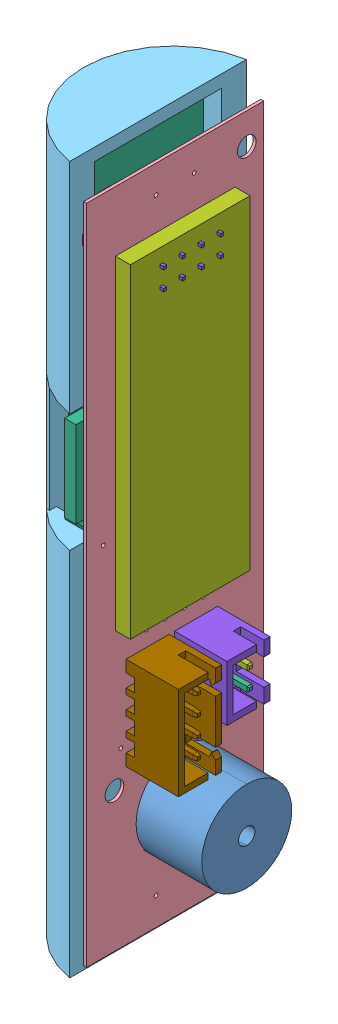
SolidWorks assembly electronics module, configuration Default. Lengths in mm.
Overall size (21.83 94.3 23.62).
277 component instances, 45 part files, 19 mates.
Components (placement in the parent):
- PCB-1: PCB [Default] at (20.7064 167.5504 -10.283) x (0 -1 0) z (-1 0 0) size (88.26 23.62 14)
  - R05-1: R05 [Default] at origin size (0.95 1.7 0.6)
    - 959206216-1: 959206216 [Default] at (123.9521 73.9609 0) size (0.95 0.27 0.6)
      - Extruded-1: Extruded [Default] at origin size (0.95 0.27 0.6)
    - 959206352-1: 959206352 [Default] at (123.9521 74.6759 0) size (0.95 1.16 0.6)
      - Extruded-1-1: Extruded-1 [Default] at origin size (0.95 1.16 0.6)
    - 959206216-2: 959206216 [Default] at (123.9521 75.3909 0) size (0.95 0.27 0.6)
      - Extruded-1: Extruded [Default] at origin size (0.95 0.27 0.6)
  - R04-1: R04 [Default] at origin size (0.95 1.7 0.6)
    - 959206216-1: 959206216 [Default] at (141.478 81.581 0) size (0.95 0.27 0.6)
      - Extruded-1: Extruded [Default] at origin size (0.95 0.27 0.6)
    - 959206352-1: 959206352 [Default] at (141.478 82.296 0) size (0.95 1.16 0.6)
      - Extruded-1-1: Extruded-1 [Default] at origin size (0.95 1.16 0.6)
    - 959206216-2: 959206216 [Default] at (141.478 83.011 0) size (0.95 0.27 0.6)
      - Extruded-1: Extruded [Default] at origin size (0.95 0.27 0.6)
  - R03-1: R03 [Default] at origin size (3.35 1.75 0.75)
    - 959206760-1: 959206760 [Default] at (147.8506 77.6516 0) size (0.49 1.75 0.75)
      - Extruded-2-1: Extruded-2 [Default] at origin size (0.49 1.75 0.75)
    - 959206896-1: 959206896 [Default] at (149.2781 77.6516 0) size (2.36 1.75 0.75)
      - Extruded-3-1: Extruded-3 [Default] at origin size (2.36 1.75 0.75)
    - 959206760-2: 959206760 [Default] at (150.7056 77.6516 0) size (0.49 1.75 0.75)
      - Extruded-2-1: Extruded-2 [Default] at origin size (0.49 1.75 0.75)
  - R02-1: R02 [Default] at origin size (1.75 3.35 0.75)
    - 959207032-1: 959207032 [Default] at (128.1431 81.3844 0) size (1.75 0.49 0.75)
      - Extruded-4-1: Extruded-4 [Default] at origin size (1.75 0.49 0.75)
    - 959207168-1: 959207168 [Default] at (128.1431 79.9569 0) size (1.75 2.36 0.75)
      - Extruded-5-1: Extruded-5 [Default] at origin size (1.75 2.36 0.75)
    - 959207032-2: 959207032 [Default] at (128.1431 78.5294 0) size (1.75 0.49 0.75)
      - Extruded-4-1: Extruded-4 [Default] at origin size (1.75 0.49 0.75)
  - R01-1: R01 [Default] at origin size (3.35 1.75 0.75)
    - 959206760-1: 959206760 [Default] at (117.3285 91.9479 0) size (0.49 1.75 0.75)
      - Extruded-2-1: Extruded-2 [Default] at origin size (0.49 1.75 0.75)
    - 959206896-1: 959206896 [Default] at (115.901 91.9479 0) size (2.36 1.75 0.75)
      - Extruded-3-1: Extruded-3 [Default] at origin size (2.36 1.75 0.75)
    - 959206760-2: 959206760 [Default] at (114.4735 91.9479 0) size (0.49 1.75 0.75)
      - Extruded-2-1: Extruded-2 [Default] at origin size (0.49 1.75 0.75)
  - U3-1: U3 [Default] at origin size (43.25 15.95 5.5)
    - 959206080-1: 959206080 [Default] at (102.177 84.441 -2.3912) size (43.25 15.95 2)
      - Extruded-6-1: Extruded-6 [Default] at origin size (43.25 15.95 2)
    - 959205944-1: 959205944 [Default] at (85.217 88.291 -2.8912) size (0.4 0.4 5.5)
      - Extruded-7-1: Extruded-7 [Default] at origin size (0.4 0.4 5.5)
    - 959205944-2: 959205944 [Default] at (85.217 85.751 -2.8912) size (0.4 0.4 5.5)
      - Extruded-7-1: Extruded-7 [Default] at origin size (0.4 0.4 5.5)
    - 959205944-3: 959205944 [Default] at (82.677 88.291 -2.8912) size (0.4 0.4 5.5)
      - Extruded-7-1: Extruded-7 [Default] at origin size (0.4 0.4 5.5)
    - 959205944-4: 959205944 [Default] at (82.677 85.751 -2.8912) size (0.4 0.4 5.5)
      - Extruded-7-1: Extruded-7 [Default] at origin size (0.4 0.4 5.5)
    - 959205944-5: 959205944 [Default] at (85.217 83.211 -2.8912) size (0.4 0.4 5.5)
      - Extruded-7-1: Extruded-7 [Default] at origin size (0.4 0.4 5.5)
    - 959205944-6: 959205944 [Default] at (85.217 80.671 -2.8912) size (0.4 0.4 5.5)
      - Extruded-7-1: Extruded-7 [Default] at origin size (0.4 0.4 5.5)
    - 959205944-7: 959205944 [Default] at (82.677 83.211 -2.8912) size (0.4 0.4 5.5)
      - Extruded-7-1: Extruded-7 [Default] at origin size (0.4 0.4 5.5)
    - 959205944-8: 959205944 [Default] at (82.677 80.671 -2.8912) size (0.4 0.4 5.5)
      - Extruded-7-1: Extruded-7 [Default] at origin size (0.4 0.4 5.5)
  - R11-1: R11 [Default] at origin size (1.35 2.2 0.7)
    - 959207304-1: 959207304 [Default] at (133.9849 94.0691 0) size (1.35 0.42 0.7)
      - Extruded-8-1: Extruded-8 [Default] at origin size (1.35 0.42 0.7)
    - 959207440-1: 959207440 [Default] at (133.9849 93.1791 0) size (1.35 1.36 0.7)
      - Extruded-9-1: Extruded-9 [Default] at origin size (1.35 1.36 0.7)
    - 959207304-2: 959207304 [Default] at (133.9849 92.2891 0) size (1.35 0.42 0.7)
      - Extruded-8-1: Extruded-8 [Default] at origin size (1.35 0.42 0.7)
  - Q3-1: Q3 [Default] at origin size (1.4 3 1)
    - 959206624-1: 959206624 [Default] at (105.664 90.805 0.1) size (1.4 3 1)
      - Extruded-10-1: Extruded-10 [Default] at origin size (1.4 3 1)
  - P6-1: P6 [Default] at origin size (16.31 15.21 2.47)
    - User Library-Micro SD-1: User Library-Micro SD [Default] at (103.6713 76.9862 0.04) x (-1 0 0) z (0 0 1) size (16.31 15.21 2.47)
  - Q1-1: Q1 [Default] at origin size (3 1.4 1)
    - 959206488-1: 959206488 [Default] at (75.057 92.3634 0.1) size (3 1.4 1)
      - Extruded-11-1: Extruded-11 [Default] at origin size (3 1.4 1)
  - C1-1: C1 [Default] at origin size (3.4 1.8 1.9)
    - 959208392-1: 959208392 [Default] at (133.022 83.687 0) size (0.5 1.8 1.9)
      - Extruded-12-1: Extruded-12 [Default] at origin size (0.5 1.8 1.9)
    - 959208392-2: 959208392 [Default] at (130.122 83.687 0) size (0.5 1.8 1.9)
      - Extruded-12-1: Extruded-12 [Default] at origin size (0.5 1.8 1.9)
    - 959208256-1: 959208256 [Default] at (131.572 83.687 0) size (2.4 1.8 1.9)
      - Extruded-13-1: Extruded-13 [Default] at origin size (2.4 1.8 1.9)
  - C2-1: C2 [Default] at origin size (0.95 1.75 1)
    - 959208664-1: 959208664 [Default] at (140.8925 85.698 0) size (0.95 0.35 1)
      - Extruded-14-1: Extruded-14 [Default] at origin size (0.95 0.35 1)
    - 959208664-2: 959208664 [Default] at (140.8925 87.098 0) size (0.95 0.35 1)
      - Extruded-14-1: Extruded-14 [Default] at origin size (0.95 0.35 1)
    - 959208528-1: 959208528 [Default] at (140.8925 86.398 0) size (0.95 1.05 1)
      - Extruded-15-1: Extruded-15 [Default] at origin size (0.95 1.05 1)
  - C3-1: C3 [Default] at origin size (0.95 1.75 1)
    - 959208664-1: 959208664 [Default] at (146.558 83.0961 0) size (0.95 0.35 1)
      - Extruded-14-1: Extruded-14 [Default] at origin size (0.95 0.35 1)
    - 959208664-2: 959208664 [Default] at (146.558 84.4961 0) size (0.95 0.35 1)
      - Extruded-14-1: Extruded-14 [Default] at origin size (0.95 0.35 1)
    - 959208528-1: 959208528 [Default] at (146.558 83.7961 0) size (0.95 1.05 1)
      - Extruded-15-1: Extruded-15 [Default] at origin size (0.95 1.05 1)
  - C5-1: C5 [Default] at origin size (1.75 0.95 1)
    - 959208936-1: 959208936 [Default] at (142.772 80.518 0) size (0.35 0.95 1)
      - Extruded-16-1: Extruded-16 [Default] at origin size (0.35 0.95 1)
    - 959208936-2: 959208936 [Default] at (144.172 80.518 0) size (0.35 0.95 1)
      - Extruded-16-1: Extruded-16 [Default] at origin size (0.35 0.95 1)
    - 959208800-1: 959208800 [Default] at (143.472 80.518 0) size (1.05 0.95 1)
      - Extruded-17-1: Extruded-17 [Default] at origin size (1.05 0.95 1)
  - C6-1: C6 [Default] at origin size (1.75 0.95 1)
    - 959208800-1: 959208800 [Default] at (135.5285 81.379 0) size (1.05 0.95 1)
      - Extruded-17-1: Extruded-17 [Default] at origin size (1.05 0.95 1)
    - 959208936-1: 959208936 [Default] at (136.2285 81.379 0) size (0.35 0.95 1)
      - Extruded-16-1: Extruded-16 [Default] at origin size (0.35 0.95 1)
    - 959208936-2: 959208936 [Default] at (134.8286 81.379 0) size (0.35 0.95 1)
      - Extruded-16-1: Extruded-16 [Default] at origin size (0.35 0.95 1)
  - C7-1: C7 [Default] at origin size (0.95 1.75 1)
    - 959208528-1: 959208528 [Default] at (145.288 83.8282 0) size (0.95 1.05 1)
      - Extruded-15-1: Extruded-15 [Default] at origin size (0.95 1.05 1)
    - 959208664-1: 959208664 [Default] at (145.288 83.1282 0) size (0.95 0.35 1)
      - Extruded-14-1: Extruded-14 [Default] at origin size (0.95 0.35 1)
    - 959208664-2: 959208664 [Default] at (145.288 84.5282 0) size (0.95 0.35 1)
      - Extruded-14-1: Extruded-14 [Default] at origin size (0.95 0.35 1)
  - C8-1: C8 [Default] at origin size (1.45 2.2 1)
    - 959207984-1: 959207984 [Default] at (115.697 77.2073 0) size (1.45 1.2 1)
      - Extruded-18-1: Extruded-18 [Default] at origin size (1.45 1.2 1)
    - 959207848-1: 959207848 [Default] at (115.697 78.0573 0) size (1.45 0.5 1)
      - Extruded-19-1: Extruded-19 [Default] at origin size (1.45 0.5 1)
    - 959207848-2: 959207848 [Default] at (115.697 76.3573 0) size (1.45 0.5 1)
      - Extruded-19-1: Extruded-19 [Default] at origin size (1.45 0.5 1)
  - C9-1: C9 [Default] at origin size (0.95 1.75 1)
    - 959208528-1: 959208528 [Default] at (108.577 76.835 0) size (0.95 1.05 1)
      - Extruded-15-1: Extruded-15 [Default] at origin size (0.95 1.05 1)
    - 959208664-1: 959208664 [Default] at (108.577 76.135 0) size (0.95 0.35 1)
      - Extruded-14-1: Extruded-14 [Default] at origin size (0.95 0.35 1)
    - 959208664-2: 959208664 [Default] at (108.577 77.535 0) size (0.95 0.35 1)
      - Extruded-14-1: Extruded-14 [Default] at origin size (0.95 0.35 1)
  - C10-1: C10 [Default] at origin size (0.95 1.75 1)
    - 959208664-1: 959208664 [Default] at (109.7632 77.5843 0) size (0.95 0.35 1)
      - Extruded-14-1: Extruded-14 [Default] at origin size (0.95 0.35 1)
    - 959208664-2: 959208664 [Default] at (109.7632 76.1843 0) size (0.95 0.35 1)
      - Extruded-14-1: Extruded-14 [Default] at origin size (0.95 0.35 1)
    - 959208528-1: 959208528 [Default] at (109.7632 76.8843 0) size (0.95 1.05 1)
      - Extruded-15-1: Extruded-15 [Default] at origin size (0.95 1.05 1)
  - C11-1: C11 [Default] at origin size (0.95 1.75 1)
    - 959208664-1: 959208664 [Default] at (122.4827 75.652 0) size (0.95 0.35 1)
      - Extruded-14-1: Extruded-14 [Default] at origin size (0.95 0.35 1)
    - 959208664-2: 959208664 [Default] at (122.4827 77.052 0) size (0.95 0.35 1)
      - Extruded-14-1: Extruded-14 [Default] at origin size (0.95 0.35 1)
    - 959208528-1: 959208528 [Default] at (122.4827 76.352 0) size (0.95 1.05 1)
      - Extruded-15-1: Extruded-15 [Default] at origin size (0.95 1.05 1)
  - C12-1: C12 [Default] at origin size (1.75 0.95 1)
    - 959208936-1: 959208936 [Default] at (92.521 76.327 0) size (0.35 0.95 1)
      - Extruded-16-1: Extruded-16 [Default] at origin size (0.35 0.95 1)
    - 959208936-2: 959208936 [Default] at (91.121 76.327 0) size (0.35 0.95 1)
      - Extruded-16-1: Extruded-16 [Default] at origin size (0.35 0.95 1)
    - 959208800-1: 959208800 [Default] at (91.821 76.327 0) size (1.05 0.95 1)
      - Extruded-17-1: Extruded-17 [Default] at origin size (1.05 0.95 1)
  - P1-1: P1 [Default] at origin size (7.4 5.75 10.4)
    - P1-subassembly-1-1: P1-subassembly-1 [Default] at (131.5051 81.6569 -0.3912) x (-1 0 0) z (0 -1 0) size (7.4 10.4 5.75)
      - User Library-JST B2B-XH-A-1: User Library-JST B2B-XH-A [Default] at origin size (0.64 3.4 0.64)
      - User Library-JST B2B-XH-A-1-1: User Library-JST B2B-XH-A-1 [Default] at origin size (0.64 3.4 0.64)
      - User Library-JST B2B-XH-A-2-1: User Library-JST B2B-XH-A-2 [Default] at origin size (0.64 4.5 0.64)
      - User Library-JST B2B-XH-A-3-1: User Library-JST B2B-XH-A-3 [Default] at origin size (0.64 4.5 0.64)
      - User Library-JST B2B-XH-A-4-1: User Library-JST B2B-XH-A-4 [Default] at origin size (7.4 7 5.75)
  - P3-1: P3 [Default] at origin size (12.4 5.75 10.4)
    - SW3dPS-jst-b4b-xh-a-1-1: SW3dPS-jst-b4b-xh-a-1 [Default] at (134.0049 88.1301 -0.3912) x (-1 0 0) z (0 -1 0) size (12.4 10.4 5.75)
  - P4-1: P4 [Default] at origin
    - connector-1: connector [Default] at (76.2639 56.9549 -0.3912) x (0 1 0) z (0 0 -1)
  - P5-1: P5 [Default] at origin
    - connector-1: connector [Default] at (157.0351 111.9551 -0.3912) x (0 -1 0) z (0 0 -1)
  - Q2-1: Q2 [Default] at origin size (1.4 3 1)
    - 959206624-1: 959206624 [Default] at (158.496 90.17 0.1) size (1.4 3 1)
      - Extruded-10-1: Extruded-10 [Default] at origin size (1.4 3 1)
  - R1-1: R1 [Default] at origin size (0.95 1.7 0.6)
    - 959206216-1: 959206216 [Default] at (142.6211 77.6287 0) size (0.95 0.27 0.6)
      - Extruded-1: Extruded [Default] at origin size (0.95 0.27 0.6)
    - 959206352-1: 959206352 [Default] at (142.6211 78.3437 0) size (0.95 1.16 0.6)
      - Extruded-1-1: Extruded-1 [Default] at origin size (0.95 1.16 0.6)
    - 959206216-2: 959206216 [Default] at (142.6211 79.0587 0) size (0.95 0.27 0.6)
      - Extruded-1: Extruded [Default] at origin size (0.95 0.27 0.6)
  - R2-1: R2 [Default] at origin size (1.4 2.15 0.7)
    - 959208120-1: 959208120 [Default] at (111.8912 75.852 0) size (1.4 2.15 0.7)
      - Extruded-20-1: Extruded-20 [Default] at origin size (1.4 2.15 0.7)
  - R3-1: R3 [Default] at origin size (1.35 2.2 0.7)
    - 959207304-1: 959207304 [Default] at (114.1729 78.1061 0) size (1.35 0.42 0.7)
      - Extruded-8-1: Extruded-8 [Default] at origin size (1.35 0.42 0.7)
    - 959207440-1: 959207440 [Default] at (114.1729 77.2161 0) size (1.35 1.36 0.7)
      - Extruded-9-1: Extruded-9 [Default] at origin size (1.35 1.36 0.7)
    - 959207304-2: 959207304 [Default] at (114.1729 76.3261 0) size (1.35 0.42 0.7)
      - Extruded-8-1: Extruded-8 [Default] at origin size (1.35 0.42 0.7)
  - R4-1: R4 [Default] at origin size (1.7 0.95 0.6)
    - 959209072-1: 959209072 [Default] at (119.5871 82.2961 0) size (0.27 0.95 0.6)
      - Extruded-21-1: Extruded-21 [Default] at origin size (0.27 0.95 0.6)
    - 959209208-1: 959209208 [Default] at (118.8721 82.2961 0) size (1.16 0.95 0.6)
      - Extruded-22-1: Extruded-22 [Default] at origin size (1.16 0.95 0.6)
    - 959209072-2: 959209072 [Default] at (118.1571 82.2961 0) size (0.27 0.95 0.6)
      - Extruded-21-1: Extruded-21 [Default] at origin size (0.27 0.95 0.6)
  - R5-1: R5 [Default] at origin size (0.95 1.7 0.6)
    - 959206216-1: 959206216 [Default] at (120.9041 81.6699 0) size (0.95 0.27 0.6)
      - Extruded-1: Extruded [Default] at origin size (0.95 0.27 0.6)
    - 959206352-1: 959206352 [Default] at (120.9041 82.3849 0) size (0.95 1.16 0.6)
      - Extruded-1-1: Extruded-1 [Default] at origin size (0.95 1.16 0.6)
    - 959206216-2: 959206216 [Default] at (120.9041 83.0999 0) size (0.95 0.27 0.6)
      - Extruded-1: Extruded [Default] at origin size (0.95 0.27 0.6)
  - R6-1: R6 [Default] at origin size (1.4 2.15 0.7)
    - 959208120-1: 959208120 [Default] at (122.9827 82.385 0) size (1.4 2.15 0.7)
      - Extruded-20-1: Extruded-20 [Default] at origin size (1.4 2.15 0.7)
  - R8-1: R8 [Default] at origin size (2.51 2.51 0.7)
    - 959207576-1: 959207576 [Default] at (78.6187 92.1936 0) size (1.25 1.25 0.7)
      - Extruded-23-1: Extruded-23 [Default] at origin size (1.25 1.25 0.7)
    - 959207712-1: 959207712 [Default] at (79.248 92.8229 0) size (1.92 1.92 0.7)
      - Extruded-24-1: Extruded-24 [Default] at origin size (1.92 1.92 0.7)
    - 959207576-2: 959207576 [Default] at (79.8773 93.4522 0) size (1.25 1.25 0.7)
      - Extruded-23-1: Extruded-23 [Default] at origin size (1.25 1.25 0.7)
  - R13-1: R13 [Default] at origin size (2.2 1.35 0.7)
    - 959209344-1: 959209344 [Default] at (105.4089 93.8529 0) size (0.42 1.35 0.7)
      - Extruded-25-1: Extruded-25 [Default] at origin size (0.42 1.35 0.7)
    - 959209480-1: 959209480 [Default] at (106.2989 93.8529 0) size (1.36 1.35 0.7)
      - Extruded-26-1: Extruded-26 [Default] at origin size (1.36 1.35 0.7)
    - 959209344-2: 959209344 [Default] at (107.1889 93.8529 0) size (0.42 1.35 0.7)
      - Extruded-25-1: Extruded-25 [Default] at origin size (0.42 1.35 0.7)
  - R7-1: R7 [Default] at origin size (2.2 1.35 0.7)
    - 959209344-1: 959209344 [Default] at (76.5821 79.5961 0) size (0.42 1.35 0.7)
      - Extruded-25-1: Extruded-25 [Default] at origin size (0.42 1.35 0.7)
    - 959209480-1: 959209480 [Default] at (75.6921 79.5961 0) size (1.36 1.35 0.7)
      - Extruded-26-1: Extruded-26 [Default] at origin size (1.36 1.35 0.7)
    - 959209344-2: 959209344 [Default] at (74.8021 79.5961 0) size (0.42 1.35 0.7)
      - Extruded-25-1: Extruded-25 [Default] at origin size (0.42 1.35 0.7)
  - R9-1: R9 [Default] at origin size (1.35 2.2 0.7)
    - 959207304-1: 959207304 [Default] at (77.5971 95.5049 0) size (1.35 0.42 0.7)
      - Extruded-8-1: Extruded-8 [Default] at origin size (1.35 0.42 0.7)
    - 959207440-1: 959207440 [Default] at (77.5971 94.6149 0) size (1.35 1.36 0.7)
      - Extruded-9-1: Extruded-9 [Default] at origin size (1.35 1.36 0.7)
    - 959207304-2: 959207304 [Default] at (77.5971 93.7249 0) size (1.35 0.42 0.7)
      - Extruded-8-1: Extruded-8 [Default] at origin size (1.35 0.42 0.7)
  - R14-1: R14 [Default] at origin size (1.35 2.2 0.7)
    - 959207304-1: 959207304 [Default] at (110.6132 93.495 0) size (1.35 0.42 0.7)
      - Extruded-8-1: Extruded-8 [Default] at origin size (1.35 0.42 0.7)
    - 959207440-1: 959207440 [Default] at (110.6132 92.605 0) size (1.35 1.36 0.7)
      - Extruded-9-1: Extruded-9 [Default] at origin size (1.35 1.36 0.7)
    - 959207304-2: 959207304 [Default] at (110.6132 91.715 0) size (1.35 0.42 0.7)
      - Extruded-8-1: Extruded-8 [Default] at origin size (1.35 0.42 0.7)
  - R10-1: R10 [Default] at origin size (3.35 1.75 0.75)
    - 959206760-1: 959206760 [Default] at (152.7506 83.5661 0) size (0.49 1.75 0.75)
      - Extruded-2-1: Extruded-2 [Default] at origin size (0.49 1.75 0.75)
    - 959206896-1: 959206896 [Default] at (154.1781 83.5661 0) size (2.36 1.75 0.75)
      - Extruded-3-1: Extruded-3 [Default] at origin size (2.36 1.75 0.75)
    - 959206760-2: 959206760 [Default] at (155.6056 83.5661 0) size (0.49 1.75 0.75)
      - Extruded-2-1: Extruded-2 [Default] at origin size (0.49 1.75 0.75)
  - R12-1: R12 [Default] at origin size (1.35 2.2 0.7)
    - 959207304-1: 959207304 [Default] at (152.7811 87.2879 0) size (1.35 0.42 0.7)
      - Extruded-8-1: Extruded-8 [Default] at origin size (1.35 0.42 0.7)
    - 959207440-1: 959207440 [Default] at (152.7811 86.3979 0) size (1.35 1.36 0.7)
      - Extruded-9-1: Extruded-9 [Default] at origin size (1.35 1.36 0.7)
    - 959207304-2: 959207304 [Default] at (152.7811 85.5079 0) size (1.35 0.42 0.7)
      - Extruded-8-1: Extruded-8 [Default] at origin size (1.35 0.42 0.7)
  - U1-1: U1 [Default] at origin size (1.75 3 1.45)
    - 959209616-1: 959209616 [Default] at (137.668 84.449 0) size (1.75 3 1.45)
      - Extruded-27-1: Extruded-27 [Default] at origin size (1.75 3 1.45)
  - U4-1: U4 [Default] at origin size (7 7 1.2)
    - 959209752-1: 959209752 [Default] at (110.9632 83.702 0) size (7 7 1.2)
      - Extruded-28-1: Extruded-28 [Default] at origin size (7 7 1.2)
  - BUZ1-1: BUZ1 [Default] at origin size (12 12 14)
    - SW3dPS-WST-1203UX-1: SW3dPS-WST-1203UX [Default] at (146.685 84.5049 -0.4912) x (0 -1 0) z (1 0 0) size (12 14 12)
  - C4-1: C4 [Default] at origin size (0.95 1.75 1)
    - 959208528-1: 959208528 [Default] at (127.791 83.885 0) size (0.95 1.05 1)
      - Extruded-15-1: Extruded-15 [Default] at origin size (0.95 1.05 1)
    - 959208664-1: 959208664 [Default] at (127.791 83.185 0) size (0.95 0.35 1)
      - Extruded-14-1: Extruded-14 [Default] at origin size (0.95 0.35 1)
    - 959208664-2: 959208664 [Default] at (127.791 84.585 0) size (0.95 0.35 1)
      - Extruded-14-1: Extruded-14 [Default] at origin size (0.95 0.35 1)
  - D1-1: D1 [Default] at origin size (1.45 2.2 1.4)
    - 959209888-1: 959209888 [Default] at (77.089 89.876 0) size (1.45 2.2 1.4)
      - Extruded-29-1: Extruded-29 [Default] at origin size (1.45 2.2 1.4)
  - D2-1: D2 [Default] at origin size (2.2 1.45 1.4)
    - 959210024-1: 959210024 [Default] at (155.107 90.769 0) size (2.2 1.45 1.4)
      - Extruded-30-1: Extruded-30 [Default] at origin size (2.2 1.45 1.4)
  - D3-1: D3 [Default] at origin size (1.45 2.2 1.4)
    - 959209888-1: 959209888 [Default] at (108.585 90.769 0) size (1.45 2.2 1.4)
      - Extruded-29-1: Extruded-29 [Default] at origin size (1.45 2.2 1.4)
  - Board-1: Board [Default] at origin size (88.26 23.62 0.39)
- cross recessed binding head screw_jis-1: cross recessed binding head screw_jis [JIS B 1111 Binding head screw M2 x 6 --6S] at (22.2976 10.6684 65.893) x (-1 0 0) z (0 -0.924225 -0.381849) size (7.17 4.3 4.3) (hidden)
- cross recessed binding head screw_jis-4: cross recessed binding head screw_jis [JIS B 1111 Binding head screw M2 x 6 --6S] at (22.2976 90.9084 64.617) x (-1 0 0) z (0 -0.85199 -0.523557) size (7.17 4.3 4.3) (hidden)
- cross recessed binding head screw_jis-5: cross recessed binding head screw_jis [JIS B 1111 Binding head screw M2 x 6 --6S] at (22.2976 25.3225 82.261) x (-1 0 0) z (0 -0.77839 -0.627782) size (7.17 4.3 4.3) (hidden)
- electronics holder-2: electronics holder [Default] at (20.8164 4.4009 74.172) size (9.95 94.3 23.56)
- camera-1: camera [Default] at (15.3664 565.0334 -207.5796) x (0 1 0) z (0 0 -1) size (54 11.5 19.4)
- LED 3W-1: LED 3W [Default] at (14.0164 25.4867 74.172) x (0 1 0) z (0 0 1) size (14.67 5.4 8)
Mates (geometry in assembly coordinates):
- Parallel1: parallel anti-aligned: plane of electronics holder-2 through (18.8164 97.4009 85.9534) normal (1 0 0); plane of PCB-1/Board-1 through (20.7064 95.0334 62.361) normal (-1 0 0)
- Parallel2: parallel anti-aligned: line of electronics holder-2 through (18.8164 53.7834 85.9534) axis (0 -1 0); line of PCB-1/Board-1 through (21.0976 6.7684 62.361) axis (0 1 0)
- Coincident21: coincident aligned: line of PCB-1/Board-1 through (18.8164 95.0334 74.172) axis (0 -1 0); line of electronics holder-2 through (18.8164 97.4009 74.172) axis (0 -1 0)
- Coincident5: coincident anti-aligned: plane of PCB-1/Board-1 through (21.0976 95.0334 62.361) normal (1 0 0); plane of cross recessed binding head screw_jis-1 through (21.0976 11.0502 64.9688) normal (-1 0 0)
- Concentric1: concentric anti-aligned: circle of cross recessed binding head screw_jis-1; circle of PCB-1/Board-1
- Coincident6: coincident anti-aligned: plane of PCB-1/Board-1 through (21.0976 95.0334 62.361) normal (1 0 0); plane of cross recessed binding head screw_jis-4 through (21.0976 91.4319 63.765) normal (-1 0 0)
- Concentric3: concentric aligned: circle of cross recessed binding head screw_jis-4; circle of PCB-1/Board-1
- Coincident7: coincident anti-aligned: plane of PCB-1/Board-1 through (21.0976 95.0334 62.361) normal (1 0 0); plane of cross recessed binding head screw_jis-5 through (21.0976 25.9502 81.4826) normal (-1 0 0)
- Concentric4: concentric aligned: circle of cross recessed binding head screw_jis-5; cylinder of PCB-1/Board-1 through (21.0976 25.3225 82.261) axis (1 0 0) radius 1.25
- Parallel3: parallel anti-aligned: plane of PCB-1/Board-1 through (20.7064 95.0334 62.361) normal (-1 0 0); plane of camera-1 through (16.3664 565.0334 -207.5796) normal (1 0 0)
- Parallel4: parallel aligned: plane of PCB-1/Board-1 through (21.0976 6.7684 85.983) normal (0 -1 0); plane of camera-1 through (16.3664 45.0334 82.672) normal (0 -1 0)
- Distance4: distance = 2 mm aligned: plane of camera-1 through (16.3664 97.0334 82.672) normal (0 1 0); plane of PCB-1/Board-1 through (21.0976 95.0334 62.361) normal (0 1 0)
- Tangent1: tangent: cylinder of electronics holder-2 through (20.8164 97.4009 74.172) axis (0 -1 0) radius 11.95; line of camera-1 through (8.8664 97.0334 74.172) axis (0 -1 0)
- Coincident20: coincident aligned: line of electronics holder-2 through (8.8664 97.4009 74.172) axis (0 -1 0); line of camera-1 through (8.8664 97.0334 74.172) axis (0 -1 0)
- Parallel5: parallel anti-aligned: plane of PCB-1/Board-1 through (20.7064 95.0334 62.361) normal (-1 0 0); plane of LED 3W-1 through (14.2664 25.4867 74.172) normal (1 0 0)
- Lock1: lock: unknown of PCB-1/Board-1; unknown of electronics holder-2
- Parallel7: parallel aligned: plane of PCB-1/Board-1 through (21.0976 95.0334 85.983) normal (0 0 1); plane of LED 3W-1 through (13.9664 18.4009 75.972) normal (0 0 1)
- Coincident27: coincident anti-aligned: line of electronics holder-2 through (8.8664 97.4009 74.172) axis (0 -1 0); line of LED 3W-1 through (8.8664 20.0986 74.172) axis (0 1 0)
- Distance6: distance = 14 mm aligned: plane of LED 3W-1 through (14.2664 18.4009 74.472) normal (0 -1 0); plane of electronics holder-2 through (20.8164 4.4009 74.172) normal (0 -1 0)
